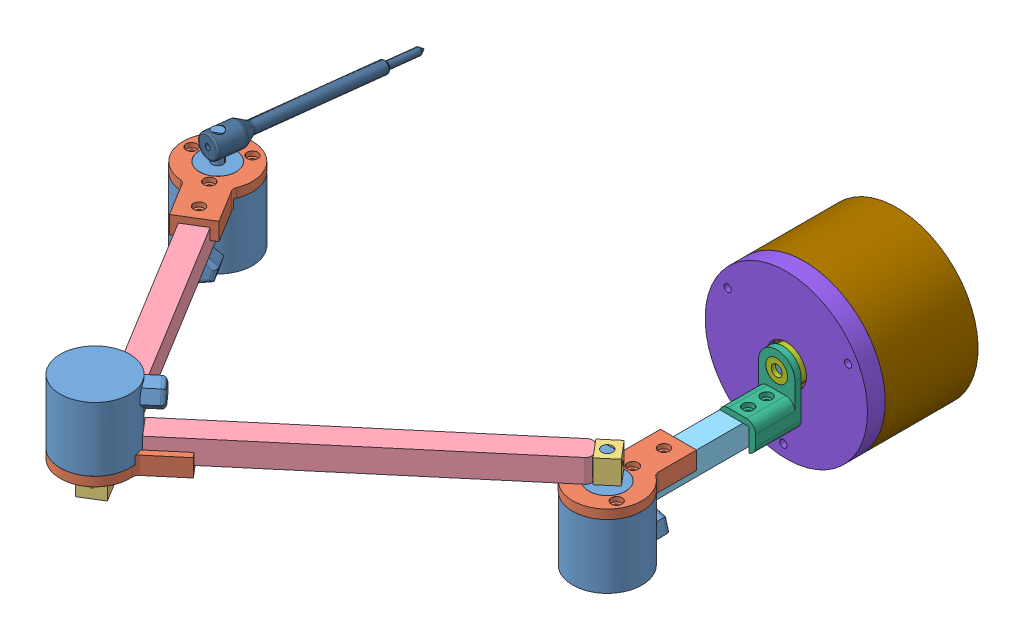
SolidWorks assembly Arm Assembly, configuration Default. Lengths in mm.
Overall size (348.01 121.24 310.58).
20 component instances, 13 part files, 54 mates.
Components (placement in the parent):
- Encoder-2: Encoder [Default] at (38.3023 -34.4108 -20.2819) size (47 38 55)
- Range of movement 20in base-1: Range of movement 20in base [Default] at (38.3023 -34.4108 123.8138) x (-1 0 0) z (0 0 -1) size (261.26 0 274.17)
- Encoder-3: Encoder [Default] at (35.0888 -83.4108 126.5182) x (0 0 -1) z (0 1 0) size (47 38 55)
- Encoder-4: Encoder [Default] at (-222.961 -83.4108 81.727) x (0.522129 0 0.852867) z (0 1 0) size (47 38 55)
- Encoder Arm Mount-1: Encoder Arm Mount [Default] at (35.0888 -43.4108 126.5182) x (1 0 0) z (0 -1 0) size (38 58 9.65)
- Encoder Arm Mount-2: Encoder Arm Mount [Default] at (-116.8559 -44.6108 255.0243) x (-0.645721 0 -0.763574) z (0 1 0) size (38 58 9.65)
- Encoder Arm Mount-3: Encoder Arm Mount [Default] at (-222.961 -43.4108 81.727) x (-0.852867 0 0.522129) z (0 -1 0) size (38 58 9.65)
- Encoder-6: Encoder [Default] at (-116.8559 -4.6108 255.0243) x (0.763574 0 -0.645721) z (0 -1 0) size (47 38 55)
- Encoder Arm Mount 2-1: Encoder Arm Mount 2 [Default] at (-116.8559 -59.6108 255.0243) x (0.522129 0 0.852867) z (0 1 0) size (21 12.7 12.7)
- Encoder Arm Mount 2-2: Encoder Arm Mount 2 [Default] at (35.0888 -28.4108 126.5182) x (0.763574 0 -0.645721) z (0 -1 0) size (21 12.7 12.7)
- radial ball bearing_68_skf-1: radial ball bearing_68_skf [SKF - 6002 - 12,SI,NC,12_68] at (38.3023 -34.4108 24.2181) x (0 0 1) z (0.001958 -0.999998 0) size (9 32 32) (hidden)
- Arm-3: Arm [Default] at (-210.8391 -53.2608 101.5083) x (0.852867 0 -0.522129) z (0.522129 0 0.852867) size (12.7 12.7 175)
- Arm-4: Arm [Default] at (31.2709 -34.7608 129.7468) x (0.645721 0 0.763574) z (-0.763574 0 0.645721) size (12.7 12.7 175)
- Arm - short-1: Arm - short [Default] at (35.0788 -53.2608 36.2782) size (12.7 12.7 71.24)
- Pivot-1: Pivot [Default] at (38.3023 -34.4108 33.5681) x (0 1 0) z (0 0 1) size (35.15 20 25)
- Bearing Hub-1: Bearing Hub [Default] at (38.3023 -34.4108 36.9681) x (0 0 1) z (-0.179563 -0.983746 0) size (17.8 18 18)
- Top Bearing Housing-1: Top Bearing Housing [Default] at (38.3023 -34.4108 31.7181) x (-0.886949 -0.461867 0) z (0 0 -1) size (88.9 88.9 9.7)
- Base Stock-2: Base Stock [Default] at (38.3023 -34.4108 -28.7819) x (0.494783 0.869017 0) z (0.869017 -0.494783 0) size (88.9 50.8 88.9)
- Pointer-1: Pointer [Default] at (-223.5561 -34.4108 86.6914) x (0.11903 0 -0.992891) z (0.992891 0 0.11903) size (106.6 12.65 12.65)
- Encoder Base Mount-1: Encoder Base Mount [Default] at (38.3023 -34.4108 22.7181) x (0.5 -0.866025 0) z (0.866025 0.5 0) size (66.29 8 62.5)
Mates (geometry in assembly coordinates):
- Coincident78: coincident anti-aligned: plane of Encoder-4 through (-222.961 -48.4108 81.727) normal (0 1 0); plane of Encoder Arm Mount-3 through (-222.961 -48.4108 81.727) normal (0 -1 0)
- Coincident80: coincident: point of Range of movement 20in base-1; line of Encoder-4 through (-222.961 -43.4108 81.727) axis (0 1 0)
- Coincident81: coincident anti-aligned: plane of Encoder Arm Mount-2 through (-116.8559 -39.6108 255.0243) normal (0 1 0); plane of Encoder-6 through (-116.8559 -39.6108 255.0243) normal (0 -1 0)
- Concentric17: concentric: cylinder of Encoder-6 through (-116.8559 -59.6108 255.0243) axis (0 1 0) radius 3; cylinder of Encoder Arm Mount 2-1 through (-116.8559 -46.9108 255.0243) axis (0 -1 0) radius 3
- Coincident89: coincident anti-aligned: line of Encoder-2 through (38.3023 -34.4108 19.7181) axis (0 0 1); line of Range of movement 20in base-1 through (38.3023 -34.4108 123.8138) axis (0 0 -1)
- Coincident90: coincident: point of Range of movement 20in base-1; line of Encoder-6 through (-116.8559 -44.6108 255.0243) axis (0 -1 0)
- Parallel24: parallel: line of Range of movement 20in base-1 through (38.3023 -34.4108 123.8138) axis (-0.763574 0 0.645721); line of Encoder Arm Mount-2 through (-87.0765 -34.7508 229.8412) axis (-0.763574 0 0.645721)
- Parallel25: parallel anti-aligned: line of Range of movement 20in base-1 through (38.3023 -34.4108 123.8138) axis (0 0 -1); line of Encoder Arm Mount-1 through (35.0888 -53.2708 87.5182) axis (0 0 1)
- Coincident94: coincident: point of Encoder-2; point of Range of movement 20in base-1
- Coincident95: coincident anti-aligned: line of Encoder-2 through (38.3023 -34.4108 19.7181) axis (1 0 0); line of Range of movement 20in base-1 through (38.3023 -34.4108 19.7181) axis (-1 0 0)
- Coincident98: coincident: plane of Encoder-6 through (-116.8559 -59.6108 255.0243) normal (0 -1 0); plane of Encoder Arm Mount 2-1 through (-116.8559 -59.6108 255.0243) normal (0 -1 0)
- Concentric22: concentric aligned: cylinder of Encoder Arm Mount-2 through (-116.8559 -34.9607 255.0243) axis (0 -1 0) radius 10.05; cylinder of Encoder-6 through (-116.8559 -39.6108 255.0243) axis (0 -1 0) radius 10
- Parallel26: parallel aligned: plane of Encoder Arm Mount-2 through (-93.4433 -39.6108 222.3123) normal (0.763574 0 -0.645721); plane of Encoder-6 through (-95.4758 -4.6108 236.9441) normal (0.763574 0 -0.645721)
- Concentric23: concentric aligned: cylinder of Encoder-4 through (-222.961 -48.4108 81.727) axis (0 1 0) radius 10; cylinder of Encoder Arm Mount-3 through (-222.961 -53.0608 81.727) axis (0 1 0) radius 10.05
- Parallel27: parallel aligned: plane of Encoder-4 through (-208.3414 -83.4108 105.6072) normal (0.522129 0 0.852867); plane of Encoder Arm Mount-3 through (-211.0072 -48.4108 120.137) normal (0.522129 0 0.852867)
- Concentric24: concentric: cylinder of Encoder-2 through (38.3023 -34.4108 14.7181) axis (0 0 1) radius 10; cylinder of radial ball bearing_68_skf-1 through (38.3023 -34.4108 3.5806) axis (0 0 1) radius 16
- Parallel30: parallel anti-aligned: line of Range of movement 20in base-1 through (38.3023 -34.4108 123.8138) axis (0 0 -1); line of Encoder Arm Mount-1 through (35.0888 -53.2708 87.5182) axis (0 0 1)
- Parallel31: parallel aligned: plane of Encoder-3 through (35.0888 -83.4108 98.5182) normal (0 0 -1); plane of Encoder Arm Mount-1 through (44.9488 -48.4108 87.5182) normal (0 0 -1)
- Concentric29: concentric aligned: circle of Encoder-3; circle of Encoder Arm Mount-1
- Coincident109: coincident anti-aligned: plane of Encoder-3 through (35.0888 -48.4108 126.5182) normal (0 1 0); plane of Encoder Arm Mount-1 through (35.0888 -48.4108 126.5182) normal (0 -1 0)
- Parallel32: parallel anti-aligned: line of Range of movement 20in base-1 through (38.3023 -34.4108 123.8138) axis (0 0 -1); line of Encoder Arm Mount-1 through (35.0888 -53.2708 87.5182) axis (0 0 1)
- Concentric30: concentric: cylinder of Encoder-3 through (35.0888 -28.4108 126.5182) axis (0 -1 0) radius 3; cylinder of Encoder Arm Mount 2-2 through (35.0888 -41.1108 126.5182) axis (0 1 0) radius 3
- Coincident111: coincident: plane of Encoder-3 through (35.0888 -28.4108 126.5182) normal (0 1 0); plane of Encoder Arm Mount 2-2 through (35.0888 -28.4108 126.5182) normal (0 1 0)
- Coincident112: coincident anti-aligned: plane of Encoder Arm Mount 2-1 through (-115.4581 -57.9608 248.3059) normal (0.852867 0 -0.522129); plane of Arm-3 through (-115.4581 -48.5608 248.3059) normal (-0.852867 0 0.522129)
- Coincident113: coincident anti-aligned: plane of Encoder Arm Mount 2-1 through (-115.4581 -57.9608 248.3059) normal (0 -1 0); plane of Arm-3 through (-115.4581 -57.9608 248.3059) normal (0 1 0)
- Coincident114: coincident anti-aligned: plane of Encoder Arm Mount 2-1 through (-119.4665 -59.6108 250.7599) normal (-0.522129 0 -0.852867); plane of Arm-3 through (-119.4665 -53.2608 250.7599) normal (0.522129 0 0.852867)
- Coincident115: coincident: line of Encoder Arm Mount-3 through (-207.6163 -46.9108 94.6107) axis (-0.852867 0 0.522129); line of Arm-3 through (-208.1312 -46.9108 99.8505) axis (-0.852867 0 0.522129)
- Coincident116: coincident: plane of Encoder Arm Mount-3 through (-207.6163 -46.9108 94.6107) normal (-0.852867 0 0.522129); plane of Arm-3 through (-114.0508 -46.9108 247.4444) normal (0.852867 0 -0.522129)
- Coincident117: coincident anti-aligned: plane of Encoder Arm Mount 2-2 through (34.3058 -30.0608 133.3356) normal (0 1 0); plane of Arm-4 through (-99.3196 -30.0608 246.3367) normal (0 -1 0)
- Coincident118: coincident anti-aligned: plane of Encoder Arm Mount 2-2 through (28.2361 -30.0608 126.158) normal (-0.645721 0 -0.763574); plane of Arm-4 through (-105.3893 -30.0608 239.1591) normal (0.645721 0 0.763574)
- Coincident119: coincident anti-aligned: plane of Encoder Arm Mount 2-2 through (31.2709 -28.4108 129.7468) normal (-0.763574 0 0.645721); plane of Arm-4 through (31.2709 -34.7608 129.7468) normal (0.763574 0 -0.645721)
- Coincident120: coincident anti-aligned: plane of Encoder Arm Mount-2 through (-106.4548 -39.6108 237.8992) normal (0.645721 0 0.763574); plane of Arm-4 through (-106.4548 -28.4108 237.8992) normal (-0.645721 0 -0.763574)
- Coincident121: coincident anti-aligned: plane of Encoder Arm Mount-2 through (-102.348 -44.6108 242.7556) normal (0.763574 0 -0.645721); plane of Arm-4 through (-102.3544 -34.7608 242.7479) normal (-0.763574 0 0.645721)
- Coincident122: coincident anti-aligned: plane of Encoder Arm Mount-2 through (-106.4548 -41.1108 237.8992) normal (0 1 0); plane of Arm-4 through (-98.2541 -41.1108 247.5966) normal (0 -1 0)
- Coincident123: coincident anti-aligned: line of Encoder Arm Mount-1 through (28.7288 -46.9108 107.5182) axis (1 0 0); line of Arm - short-1 through (41.4288 -46.9108 107.5182) axis (-1 0 0)
- Coincident124: coincident anti-aligned: plane of Encoder Arm Mount-1 through (41.4488 -46.9108 107.5182) normal (0 -1 0); plane of Arm - short-1 through (41.4288 -46.9108 107.5182) normal (0 1 0)
- Coincident125: coincident anti-aligned: plane of Encoder Arm Mount-1 through (28.7288 -46.9108 107.5182) normal (1 0 0); plane of Arm - short-1 through (28.7288 -46.9108 107.5182) normal (-1 0 0)
- Concentric31: concentric: cylinder of radial ball bearing_68_skf-1 through (38.3023 -34.4108 3.5806) axis (0 0 1) radius 7.5; cylinder of Pivot-1 through (38.3023 -34.4108 37.0181) axis (0 0 -1) radius 6
- Coincident126: coincident: plane of Arm - short-1 through (41.4288 -46.9108 107.5182) normal (0 1 0); plane of Pivot-1 through (28.3023 -46.9108 37.0181) normal (0 -1 0)
- Concentric32: concentric anti-aligned: cylinder of Pivot-1 through (38.3023 -34.4108 37.0181) axis (0 0 -1) radius 6; cylinder of Bearing Hub-1 through (38.3023 -34.4108 36.9681) axis (0 0 1) radius 7.5
- Coincident127: coincident anti-aligned: plane of Pivot-1 through (38.3023 -34.4108 33.5681) normal (0 0 -1); plane of Bearing Hub-1 through (29.4486 -32.7947 33.5681) normal (0 0 1)
- Concentric33: concentric aligned: cylinder of radial ball bearing_68_skf-1 through (38.3023 -34.4108 3.5806) axis (0 0 1) radius 7.5; cylinder of Bearing Hub-1 through (38.3023 -34.4108 36.9681) axis (0 0 1) radius 7.5
- Coincident128: coincident anti-aligned: plane of radial ball bearing_68_skf-1 through (30.5023 -34.426 28.7181) normal (0 0 1); plane of Bearing Hub-1 through (30.9242 -33.064 28.7181) normal (0 0 -1)
- Concentric37: concentric: cylinder of Encoder-4 through (-222.961 -28.4108 81.727) axis (0 -1 0) radius 3; cylinder of Pointer-1 through (-222.961 -24.4108 81.727) axis (0 -1 0) radius 3
- Coincident132: coincident: point of Range of movement 20in base-1; point of Pointer-1
- Coincident133: coincident: line of Range of movement 20in base-1 through (-222.961 -34.4108 81.727) axis (0.11903 0 -0.992891); line of Pointer-1 through (-222.961 -34.4108 81.727) axis (0.11903 0 -0.992891)
- Concentric38: concentric anti-aligned: cylinder of radial ball bearing_68_skf-1 through (38.3023 -34.4108 3.5806) axis (0 0 1) radius 16; cylinder of Top Bearing Housing-1 through (38.3023 -34.4108 76.973) axis (0 0 -1) radius 16
- Coincident134: coincident anti-aligned: plane of radial ball bearing_68_skf-1 through (22.6023 -34.4415 28.7181) normal (0 0 1); plane of Top Bearing Housing-1 through (38.3023 -34.4108 28.7181) normal (0 0 -1)
- Concentric39: concentric aligned: cylinder of radial ball bearing_68_skf-1 through (38.3023 -34.4108 3.5806) axis (0 0 1) radius 16; cylinder of Encoder Base Mount-1 through (38.3023 -34.4108 14.7181) axis (0 0 1) radius 16
- Coincident135: coincident anti-aligned: plane of radial ball bearing_68_skf-1 through (24.8523 -34.4371 19.7181) normal (0 0 -1); plane of Encoder Base Mount-1 through (38.3023 -34.4108 19.7181) normal (0 0 1)
- Concentric40: concentric anti-aligned: cylinder of Encoder-2 through (50.4266 -27.4108 8.1181) axis (0 0 1) radius 1.5; cylinder of Encoder Base Mount-1 through (50.4266 -27.4108 22.7181) axis (0 0 -1) radius 1.5
- Coincident136: coincident anti-aligned: plane of Encoder-2 through (38.3023 -34.4108 14.7181) normal (0 0 1); plane of Encoder Base Mount-1 through (28.3023 -6.1265 14.7181) normal (0 0 -1)
- Concentric41: concentric anti-aligned: cylinder of Top Bearing Housing-1 through (38.3023 -34.4108 22.0181) axis (0 0 1) radius 44.45; cylinder of Base Stock-2 through (38.3023 -34.4108 22.0181) axis (0 0 -1) radius 44.45
- Coincident137: coincident anti-aligned: plane of Top Bearing Housing-1 through (38.3023 -34.4108 22.0181) normal (0 0 -1); plane of Base Stock-2 through (38.3023 -34.4108 22.0181) normal (0 0 1)
